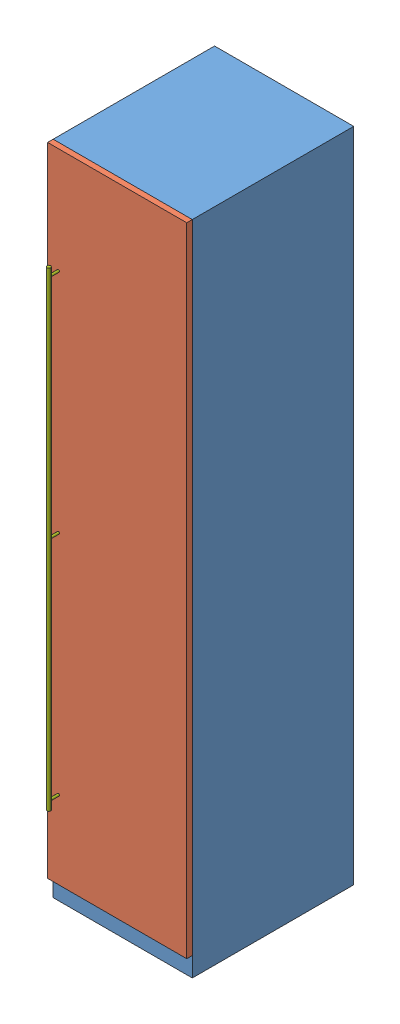
SolidWorks assembly PAX-Eingang, configuration Standard. Lengths in mm.
Overall size (500 2360 641).
9 component instances, 7 part files, 25 mates.
Components (placement in the parent):
- Pax-Korpus-Kleiderschrank-236-1: Pax-Korpus-Kleiderschrank-236 [Standard] at (-247.5936 -1124.7676 2360) size (500 2360 580)
- BALLSTAD-Tür-229-1: BALLSTAD-Tür-229 [Standard] at (-247.5936 90.2324 2650) size (500 2290 20)
- KOMPLEMENT-Regalbode-1: KOMPLEMENT-Regalbode [Standard] at (-247.5936 895.2324 2365) size (480 10 570)
- KOMPLEMENT-Kleiderstange-1: KOMPLEMENT-Kleiderstange [Standard] at (-487.5936 830.2324 2335) size (480 50 30)
- KOMPLEMENT-Regalbode-2: KOMPLEMENT-Regalbode [Standard] at (-247.5936 -434.7676 2365) size (480 10 570)
- KOMPLIMENT-Schublade-1: KOMPLIMENT-Schublade [Standard] at (-247.5936 -604.7676 2365) size (480 160 570)
- KOMPLEMENT-Netzdrahtkorb-1: KOMPLEMENT-Netzdrahtkorb [Standard] at (-247.5936 -894.7676 2365) size (480 160 570)
- KOMPLEMENT-Regalbode-3: KOMPLEMENT-Regalbode [Standard] at (-247.5936 -274.7676 2365) size (480 10 570)
- LANSA-1: LANSA [Standard] at (-458.5936 -804.7676 2704.5) x (0 0 -1) z (1 0 0) size (41 1690 13)
Mates (geometry in assembly coordinates):
- Deckungsgleich1: coincident aligned: plane of Pax-Korpus-Kleiderschrank-236-1 through (-247.5936 1235.2324 2360) normal (0 1 0); plane of BALLSTAD-Tür-229-1 through (-497.5936 1235.2324 2670) normal (0 1 0)
- Deckungsgleich2: coincident anti-aligned: plane of Pax-Korpus-Kleiderschrank-236-1 through (-497.5936 -1114.7676 2650) normal (0 0 1); plane of BALLSTAD-Tür-229-1 through (-247.5936 90.2324 2650) normal (0 0 -1)
- Deckungsgleich3: coincident aligned: plane of Pax-Korpus-Kleiderschrank-236-1 through (-497.5936 -1114.7676 2650) normal (-1 0 0); plane of BALLSTAD-Tür-229-1 through (-497.5936 -1054.7676 2670) normal (-1 0 0)
- Deckungsgleich4: coincident anti-aligned: plane of Pax-Korpus-Kleiderschrank-236-1 through (-487.5936 1225.2324 2080) normal (0 0 1); plane of KOMPLEMENT-Regalbode-1 through (-487.5936 905.2324 2080) normal (0 0 -1)
- Deckungsgleich5: coincident anti-aligned: plane of Pax-Korpus-Kleiderschrank-236-1 through (-487.5936 1225.2324 2650) normal (1 0 0); plane of KOMPLEMENT-Regalbode-1 through (-487.5936 905.2324 2650) normal (-1 0 0)
- Abstand1: distance = 320 mm anti-aligned: plane of KOMPLEMENT-Regalbode-1 through (-247.5936 905.2324 2365) normal (0 1 0); plane of Pax-Korpus-Kleiderschrank-236-1 through (-247.5936 1225.2324 2360) normal (0 -1 0)
- Deckungsgleich7: coincident: plane of Pax-Korpus-Kleiderschrank-236-1 through (-487.5936 1225.2324 2650) normal (1 0 0); plane of KOMPLEMENT-Kleiderstange-1 through (-487.5936 830.2324 2335) normal (-1 0 0)
- Abstand2: distance = 50 mm: plane of KOMPLEMENT-Kleiderstange-1 through (-467.5936 845.2324 2320) normal (0 1 0); plane of KOMPLEMENT-Regalbode-1 through (-247.5936 895.2324 2365) normal (0 -1 0)
- Abstand3: distance = 300 mm aligned: plane of KOMPLEMENT-Kleiderstange-1 through (-467.5936 795.2324 2350) normal (0 0 1); plane of Pax-Korpus-Kleiderschrank-236-1 through (-497.5936 -1114.7676 2650) normal (0 0 1)
- Deckungsgleich10: coincident anti-aligned: plane of Pax-Korpus-Kleiderschrank-236-1 through (-487.5936 1225.2324 2080) normal (0 0 1); plane of KOMPLEMENT-Regalbode-2 through (-487.5936 -424.7676 2080) normal (0 0 -1)
- Deckungsgleich11: coincident anti-aligned: plane of Pax-Korpus-Kleiderschrank-236-1 through (-487.5936 1225.2324 2650) normal (1 0 0); plane of KOMPLEMENT-Regalbode-2 through (-487.5936 -424.7676 2650) normal (-1 0 0)
- Abstand4: distance = 1220 mm anti-aligned: plane of KOMPLEMENT-Kleiderstange-1 through (-467.5936 795.2324 2320) normal (0 -1 0); plane of KOMPLEMENT-Regalbode-2 through (-247.5936 -424.7676 2365) normal (0 1 0)
- Deckungsgleich13: coincident anti-aligned: plane of Pax-Korpus-Kleiderschrank-236-1 through (-487.5936 1225.2324 2080) normal (0 0 1); plane of KOMPLIMENT-Schublade-1 through (-487.5936 -594.7676 2080) normal (0 0 -1)
- Deckungsgleich14: coincident anti-aligned: plane of Pax-Korpus-Kleiderschrank-236-1 through (-487.5936 1225.2324 2650) normal (1 0 0); plane of KOMPLIMENT-Schublade-1 through (-487.5936 -594.7676 2650) normal (-1 0 0)
- Abstand5: distance = 10 mm anti-aligned: plane of KOMPLIMENT-Schublade-1 through (-247.5936 -444.7676 2365) normal (0 1 0); plane of KOMPLEMENT-Regalbode-2 through (-247.5936 -434.7676 2365) normal (0 -1 0)
- Deckungsgleich16: coincident: plane of Pax-Korpus-Kleiderschrank-236-1 through (-247.5936 -1054.7676 2360) normal (0 1 0); plane of KOMPLEMENT-Netzdrahtkorb-1 through (-247.5936 -1054.7676 2365) normal (0 -1 0)
- Deckungsgleich17: coincident: plane of Pax-Korpus-Kleiderschrank-236-1 through (-487.5936 1225.2324 2650) normal (1 0 0); line of KOMPLEMENT-Netzdrahtkorb-1 through (-487.5936 -894.7676 2080) axis (0 0 1)
- Deckungsgleich18: coincident: plane of Pax-Korpus-Kleiderschrank-236-1 through (-487.5936 1225.2324 2080) normal (0 0 1); line of KOMPLEMENT-Netzdrahtkorb-1 through (-7.5936 -894.7676 2080) axis (-1 0 0)
- Deckungsgleich19: coincident: plane of Pax-Korpus-Kleiderschrank-236-1 through (-7.5936 1225.2324 2080) normal (-1 0 0); plane of KOMPLEMENT-Regalbode-3 through (-7.5936 -264.7676 2650) normal (1 0 0)
- Deckungsgleich20: coincident anti-aligned: plane of Pax-Korpus-Kleiderschrank-236-1 through (-487.5936 1225.2324 2080) normal (0 0 1); plane of KOMPLEMENT-Regalbode-3 through (-487.5936 -264.7676 2080) normal (0 0 -1)
- Abstand7: distance = 150 mm: plane of KOMPLEMENT-Regalbode-3 through (-247.5936 -274.7676 2365) normal (0 -1 0); plane of KOMPLEMENT-Regalbode-2 through (-247.5936 -424.7676 2365) normal (0 1 0)
- Deckungsgleich21: coincident: plane of BALLSTAD-Tür-229-1 through (-247.5936 90.2324 2670) normal (0 0 1); plane of LANSA-1 through (-458.5936 855.2324 2670) normal (0 0 -1)
- Parallel1: parallel: line of BALLSTAD-Tür-229-1 through (-497.5936 1235.2324 2670) axis (0 -1 0); cylinder of LANSA-1 through (-458.5936 885.2324 2704.5) axis (0 -1 0) radius 6.5
- Abstand8: distance = 250 mm: plane of LANSA-1 through (-458.5936 -804.7676 2704.5) normal (0 -1 0); plane of BALLSTAD-Tür-229-1 through (-497.5936 -1054.7676 2670) normal (0 -1 0)
- Abstand9: distance = 35 mm: cylinder of LANSA-1 through (-458.5936 -774.7676 2670) axis (0 0 1) radius 4; line of BALLSTAD-Tür-229-1 through (-497.5936 1235.2324 2670) axis (0 -1 0)
